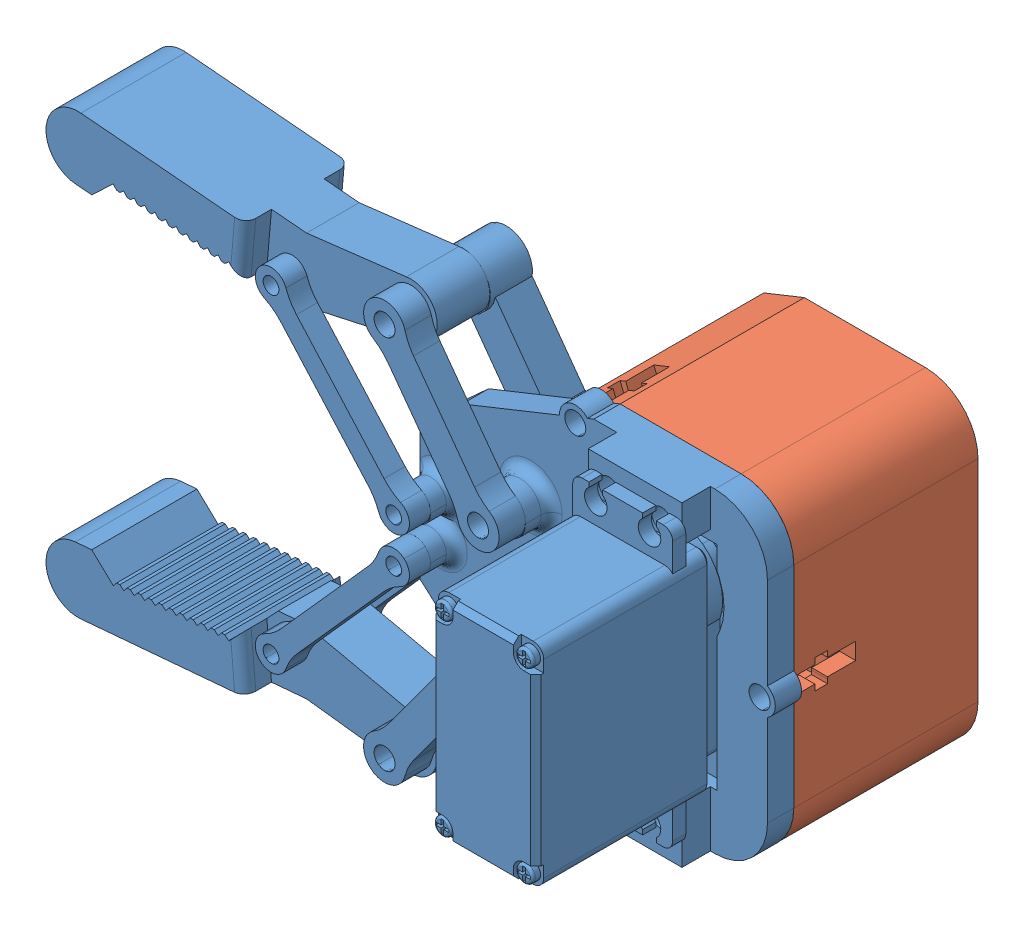
SolidWorks assembly Assemblage44, configuration Défaut. Lengths in mm.
Overall size (128.58 83.29 74.42).
2 component instances, 2 part files, 3 mates.
Components (placement in the parent):
- gripper_complet-1: gripper_complet [Défaut] at (35.0891 19.8429 -203.3605) size (128.58 83.29 47.42)
- cover-1: cover [Défaut] at (6.4755 39.3491 -172.3583) x (-1 0 0) z (0 0 -1) size (40.71 60 35)
Mates (geometry in assembly coordinates):
- Coïncidente1: coincident: plane of gripper_complet-1 through (25.7527 27.8783 -152.3583) normal (0 0 -1); plane of cover-1 through (62.7759 40.3868 -152.3583) normal (0 0 1)
- Coïncidente2: coincident: line of gripper_complet-1 through (72.7759 17.7905 -152.3583) axis (0 -1 0); line of cover-1 through (72.7759 18.7868 -152.3583) axis (0 -1 0)
- Coïncidente3: coincident aligned: plane of gripper_complet-1 through (44.7759 -9.6132 -147.3583) normal (0 -1 0); plane of cover-1 through (39.7759 -9.6132 -187.3583) normal (0 -1 0)
